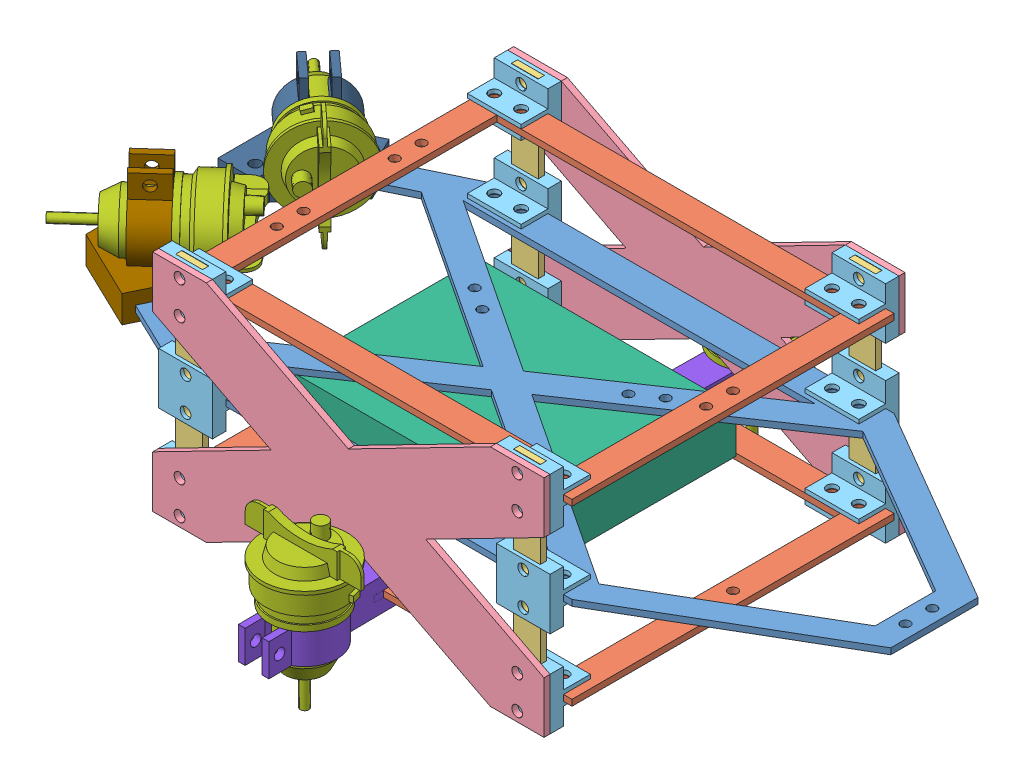
SolidWorks assembly Assem1, configuration Default. Lengths in mm.
Overall size (594.33 204.56 424.5).
30 component instances, 10 part files, 157 mates.
Components (placement in the parent):
- Middle Frame-1: Middle Frame [Default] at (261.8688 289.8887 390.3727) size (550 4.5 240)
- Top and Bottom Frames-1: Top and Bottom Frames [Default] at (113.8268 225.3887 390.3727) size (296 4.5 240)
- Top and Bottom Frames-2: Top and Bottom Frames [Default] at (113.8268 354.3887 390.3727) size (296 4.5 240)
- Rib-1: Rib [Default] at (261.8688 294.3887 512.9927) x (-1 0 0) z (0 0 1) size (20 167.5 4.5)
- Rib-3: Rib [Default] at (209.1848 289.8887 263.2527) size (20 167.5 4.5)
- Rib-4: Rib [Default] at (-42.4152 289.8887 262.9927) size (20 167.5 4.5)
- Rib-5: Rib [Default] at (-42.4152 291.8887 513.2527) size (20 167.5 4.5)
- Side Panels-3: Side Panels [Default] at (261.8688 354.3887 260.3727) x (-1 0 0) z (0 0 -1) size (291.6 167.5 4.5)
- Side Panels-4: Side Panels [Default] at (-42.4152 356.3887 520.3727) size (291.6 167.5 4.5)
- Joint-13: Joint [Default] at (10.2688 358.8887 390.3727) x (1 0 0) z (0 1 0) size (40 30 38.5)
- Joint-14: Joint [Default] at (10.2688 229.8887 390.3727) x (1 0 0) z (0 1 0) size (40 30 38.5)
- Joint-15: Joint [Default] at (10.2688 294.3887 390.3727) x (1 0 0) z (0 1 0) size (40 30 38.5)
- Joint-1: Joint [Default] at (261.8688 294.3887 390.3727) x (1 0 0) z (0 1 0) size (40 30 38.5)
- Joint-2: Joint [Default] at (261.8688 358.8887 390.3727) x (1 0 0) z (0 1 0) size (40 30 38.5)
- Joint-3: Joint [Default] at (261.8688 229.8887 390.3727) x (1 0 0) z (0 1 0) size (40 30 38.5)
- Joint-7: Joint [Default] at (209.2399 294.3887 390.3727) x (-1 0 0) z (0 1 0) size (40 30 38.5)
- Joint-8: Joint [Default] at (261.8688 354.3887 390.3727) x (1 0 0) z (0 -1 0) size (40 30 38.5)
- Joint-9: Joint [Default] at (261.8688 225.3887 390.3727) x (1 0 0) z (0 -1 0) size (40 30 38.5)
- Joint-10: Joint [Default] at (10.2688 354.3887 390.3727) x (1 0 0) z (0 -1 0) size (40 30 38.5)
- Joint-11: Joint [Default] at (10.2688 289.8887 390.3727) x (1 0 0) z (0 -1 0) size (40 30 38.5)
- Joint-12: Joint [Default] at (10.2688 225.3887 390.3727) x (1 0 0) z (0 -1 0) size (40 30 38.5)
- EBay-1: EBay [Default] at (261.8688 289.8887 390.3727) x (-1 0 0) z (0 -1 0) size (191.71 142.85 32)
- Thruster_CAD-2: Thruster_CAD [Default] at (-100.2352 324.4872 444.896) x (-0.743419 0 0.668826) z (0.668826 0 0.743419) size (115.62 62.99 86.36)
- Thruster_CAD-3: Thruster_CAD [Default] at (108.81 239.6387 223.1786) x (0 -1 0) z (-0.963048 0 -0.269329) size (115.62 62.99 86.36)
- Thruster_CAD-6: Thruster_CAD [Default] at (109.8463 239.6387 557.5668) x (0 -1 0) z (-1 0 0) size (115.62 62.99 86.36)
- Thruster_CAD-5: Thruster_CAD [Default] at (-100.2352 324.4872 335.8494) x (-0.743419 0 -0.668826) z (0 -1 0) size (115.62 62.99 86.36)
- Motor Mount A-2: Motor Mount A [Default] at (108.81 239.6387 223.1786) x (0.963048 0 0.269329) z (0 -1 0) size (55.77 118.28 24)
- Motor Mount A-3: Motor Mount A [Default] at (109.8463 215.6387 557.5668) x (0.963048 0 -0.269329) z (0 1 0) size (55.77 118.28 24)
- Motor Mount B1-2: Motor Mount B1 [Default] at (-100.2352 324.4872 444.896) x (-0.646037 -0.258819 -0.718087) z (-0.743419 0 0.668826) size (93.21 89.48 54.64)
- Motor Mount B2-1: Motor Mount B2 [Default] at (-100.2352 324.4872 335.8494) x (-0.646037 -0.258819 0.718087) z (0.743419 0 0.668826) size (93.21 89.48 54.64)
Mates (geometry in assembly coordinates):
- Concentric1: concentric aligned: circle of Middle Frame-1; circle of Top and Bottom Frames-2
- Parallel1: parallel aligned: line of Middle Frame-1 through (-34.1312 294.3887 510.3727) axis (1 0 0); line of Top and Bottom Frames-2 through (-34.1732 358.8887 510.3727) axis (1 0 0)
- Concentric2: concentric aligned: circle of Middle Frame-1; circle of Top and Bottom Frames-1
- Parallel2: parallel aligned: line of Middle Frame-1 through (-34.1312 294.3887 510.3727) axis (1 0 0); line of Top and Bottom Frames-1 through (-34.1732 229.8887 510.3727) axis (1 0 0)
- Distance1: distance = 60 mm: line of Top and Bottom Frames-2 through (-34.1732 354.3887 510.3727) axis (1 0 0); line of Middle Frame-1 through (-34.1312 294.3887 510.3727) axis (1 0 0)
- Distance2: distance = 60 mm: line of Top and Bottom Frames-1 through (-34.1732 229.8887 510.3727) axis (1 0 0); line of Middle Frame-1 through (-34.1312 289.8887 510.3727) axis (1 0 0)
- InPlace1: in place: plane of Middle Frame-1 through (261.8688 294.3887 390.3727) normal (0 1 0); plane of ? through (0 294.3887 0) normal (0 1 0); moOrthogonalPlaneRef_w of Middle Frame-1 through (261.8688 294.3887 390.3727) normal (0 1 0); plane of ? through (0 294.3887 0) normal (0 0 -1); plane of Middle Frame-1 through (261.8688 294.3887 390.3727) normal (0 1 0); plane of ? through (0 294.3887 0) normal (1 0 0); plane of Middle Frame-1 through (261.8688 294.3887 390.3727) normal (0 1 0); unknown of Joint-1
- Coincident5: coincident aligned: plane of ?; plane of ?
- Coincident6: coincident aligned: moOrthogonalPlaneRef_w of Middle Frame-1 through (261.8688 294.3887 390.3727) normal (0 0 -1); plane of Joint-1 through (261.8688 294.3887 390.3727) normal (0 0 -1)
- Coincident7: coincident anti-aligned: moOrthogonalPlaneRef_w of Middle Frame-1 through (261.8688 294.3887 390.3727) normal (-1 0 0); plane of Joint-1 through (261.8688 294.3887 390.3727) normal (1 0 0)
- Coincident19: coincident anti-aligned: plane of Top and Bottom Frames-2 through (-34.1732 358.8887 510.3727) normal (0 0 1); plane of Joint-2 through (261.8688 354.3887 510.3727) normal (0 0 -1)
- Concentric8: concentric aligned: circle of Top and Bottom Frames-2; circle of Part1-2
- Coincident21: coincident anti-aligned: plane of Top and Bottom Frames-2 through (113.8268 354.3887 390.3727) normal (0 -1 0); plane of Joint-2 through (261.8688 354.3887 390.3727) normal (0 1 0)
- Coincident22: coincident anti-aligned: plane of Top and Bottom Frames-1 through (-34.1732 229.8887 510.3727) normal (0 0 1); plane of Joint-3 through (261.8688 225.3887 510.3727) normal (0 0 -1)
- Concentric9: concentric aligned: circle of Top and Bottom Frames-1; circle of Part1-3
- Coincident24: coincident anti-aligned: plane of Top and Bottom Frames-1 through (113.8268 229.8887 390.3727) normal (0 1 0); plane of Joint-3 through (261.8688 229.8887 390.3727) normal (0 -1 0)
- InPlace2: in place: plane of Joint-1 through (261.8688 297.3887 512.9927) normal (0 0 1); plane of ? through (0 0 512.9927) normal (0 0 1); plane of Joint-1 through (261.8688 297.3887 512.9927) normal (0 0 1); plane of ? through (0 0 512.9927) normal (0 1 0); plane of Joint-1 through (261.8688 297.3887 512.9927) normal (0 0 1); plane of ? through (0 0 512.9927) normal (1 0 0); plane of Joint-1 through (261.8688 297.3887 512.9927) normal (0 0 1); unknown of Rib-1
- Coincident25: coincident aligned: plane of ?; plane of ?
- Coincident26: coincident aligned: moOrthogonalPlaneRef_w of Joint-1 through (261.8688 294.3887 512.9927) normal (0 -1 0); plane of Rib-1 through (261.8688 294.3887 512.9927) normal (0 -1 0)
- Coincident27: coincident anti-aligned: moOrthogonalPlaneRef_w of Joint-1 through (261.8688 294.3887 512.9927) normal (1 0 0); plane of Rib-1 through (261.8688 294.3887 512.9927) normal (-1 0 0)
- InPlace3: in place: plane of Middle Frame-1 through (261.8688 294.3887 390.3727) normal (0 1 0); plane of ? through (0 294.3887 0) normal (0 1 0); plane of Middle Frame-1 through (261.8688 294.3887 390.3727) normal (0 1 0); plane of ? through (0 294.3887 0) normal (0 0 -1); plane of Middle Frame-1 through (261.8688 294.3887 390.3727) normal (0 1 0); plane of ? through (0 294.3887 0) normal (1 0 0); plane of Middle Frame-1 through (261.8688 294.3887 390.3727) normal (0 1 0); unknown of Joint-1
- Coincident25: coincident aligned: plane of ?; plane of ?
- Coincident26: coincident aligned: moOrthogonalPlaneRef_w of Middle Frame-1 through (261.8688 294.3887 390.3727) normal (0 0 -1); plane of Part3-1 through (261.8688 294.3887 390.3727) normal (0 0 -1)
- Coincident27: coincident anti-aligned: moOrthogonalPlaneRef_w of Middle Frame-1 through (261.8688 294.3887 390.3727) normal (-1 0 0); plane of Part3-1 through (261.8688 294.3887 390.3727) normal (1 0 0)
- Coincident31: coincident anti-aligned: plane of Top and Bottom Frames-2 through (261.8268 358.8887 510.3727) normal (1 0 0); plane of Part4-1 through (261.8268 354.3887 391.9497) normal (-1 0 0)
- Coincident32: coincident anti-aligned: plane of Top and Bottom Frames-2 through (113.8268 354.3887 390.3727) normal (0 -1 0); plane of Part4-1 through (391.8268 354.3887 391.9497) normal (0 1 0)
- Concentric11: concentric aligned: circle of Top and Bottom Frames-2; circle of Part3-2
- InPlace4: in place: plane of Top and Bottom Frames-2 through (113.8268 358.8887 390.3727) normal (0 1 0); plane of ? through (0 358.8887 0) normal (0 1 0); plane of Top and Bottom Frames-2 through (113.8268 358.8887 390.3727) normal (0 1 0); plane of ? through (0 358.8887 0) normal (0 0 -1); plane of Top and Bottom Frames-2 through (113.8268 358.8887 390.3727) normal (0 1 0); plane of ? through (0 358.8887 0) normal (1 0 0); plane of Top and Bottom Frames-2 through (113.8268 358.8887 390.3727) normal (0 1 0); unknown of ?
- Coincident35: coincident aligned: plane of ?; plane of ?
- Coincident36: coincident aligned: moOrthogonalPlaneRef_w of Top and Bottom Frames-2 through (113.8268 358.8887 390.3727) normal (0 0 -1); plane of Front Rib-2 through (113.8268 358.8887 390.3727) normal (0 0 -1)
- Coincident37: coincident anti-aligned: moOrthogonalPlaneRef_w of Top and Bottom Frames-2 through (113.8268 358.8887 390.3727) normal (-1 0 0); plane of Front Rib-2 through (113.8268 358.8887 390.3727) normal (1 0 0)
- Coincident38: coincident anti-aligned: plane of Top and Bottom Frames-1 through (261.8268 229.8887 510.3727) normal (1 0 0); plane of Part4-2 through (261.8268 229.8887 388.7957) normal (-1 0 0)
- Coincident39: coincident anti-aligned: plane of Top and Bottom Frames-1 through (113.8268 225.3887 390.3727) normal (0 -1 0); plane of Part4-2 through (391.8268 225.3887 388.7957) normal (0 1 0)
- Concentric12: concentric anti-aligned: circle of Top and Bottom Frames-1; circle of Part4-2
- Coincident41: coincident anti-aligned: plane of Part4-2 through (266.8688 225.3887 386.5457) normal (0 1 0); plane of Front Rib-3 through (539.9108 225.3887 390.3727) normal (0 -1 0)
- Coincident42: coincident anti-aligned: plane of Part4-2 through (391.8268 225.3887 386.5457) normal (0 0 1); plane of Front Rib-3 through (386.8688 225.3887 386.5457) normal (0 0 -1)
- Coincident43: coincident anti-aligned: plane of Part4-2 through (276.8268 231.2277 386.5457) normal (0.50582 -0.862639 0); plane of Front Rib-3 through (498.1959 361.0305 386.5457) normal (-0.50582 0.862639 0)
- InPlace5: in place: plane of Middle Frame-1 through (261.8688 289.8887 390.3727) normal (0 -1 0); plane of ? through (0 289.8887 0) normal (0 -1 0); plane of Middle Frame-1 through (261.8688 289.8887 390.3727) normal (0 -1 0); plane of ? through (0 289.8887 0) normal (0 0 -1); plane of Middle Frame-1 through (261.8688 289.8887 390.3727) normal (0 -1 0); plane of ? through (0 289.8887 0) normal (-1 0 0); plane of Middle Frame-1 through (261.8688 289.8887 390.3727) normal (0 -1 0); unknown of EBay-1
- Coincident44: coincident aligned: plane of ?; plane of ?
- Coincident45: coincident aligned: moOrthogonalPlaneRef_w of Middle Frame-1 through (261.8688 289.8887 390.3727) normal (0 0 -1); plane of Part4^Assem1-1 through (261.8688 289.8887 390.3727) normal (0 0 -1)
- Coincident46: coincident anti-aligned: moOrthogonalPlaneRef_w of Middle Frame-1 through (261.8688 289.8887 390.3727) normal (1 0 0); plane of Part4^Assem1-1 through (261.8688 289.8887 390.3727) normal (-1 0 0)
- InPlace6: in place: plane of ? through (200.9485 144.8042 552.0146) normal (1 0 0); plane of ? through (200.9485 0 0) normal (1 0 0); plane of ? through (200.9485 144.8042 552.0146) normal (1 0 0); plane of ? through (200.9485 0 0) normal (0 1 0); plane of ? through (200.9485 144.8042 552.0146) normal (1 0 0); plane of ? through (200.9485 0 0) normal (0 0 -1); plane of ? through (264.6716 329.6787 371.9722) normal (-1 0 0); unknown of ?
- Coincident47: coincident aligned: plane of ?; plane of ?
- Coincident48: coincident aligned: moOrthogonalPlaneRef_w of Thruster_CAD-1 through (264.6716 329.6787 371.9722) normal (0 1 0); plane of Part5^Assem1-1 through (264.6716 329.6787 371.9722) normal (0 1 0)
- Coincident49: coincident anti-aligned: moOrthogonalPlaneRef_w of Thruster_CAD-1 through (264.6716 329.6787 371.9722) axis (0 0 -1); plane of Part5^Assem1-1 through (264.6716 329.6787 371.9722) normal (0 0 1)
- Tangent1: tangent aligned: plane of Top and Bottom Frames-2 through (113.8268 358.8887 390.3727) normal (0 1 0); cylinder of Thruster_CAD-1 through (413.065 329.6787 580.763) axis (-1 0 0) radius 29.21
- Parallel3: parallel aligned: plane of Top and Bottom Frames-2 through (113.8268 358.8887 390.3727) normal (0 1 0); plane of Thruster_CAD-1 through (415.605 332.8537 537.583) normal (0 1 0)
- Parallel4: parallel aligned: plane of Top and Bottom Frames-2 through (261.8268 358.8887 510.3727) normal (1 0 0); plane of Thruster_CAD-1 through (423.225 329.6787 580.763) normal (1 0 0)
- InPlace7: in place: plane of ? through (-212.6065 302.1229 334.1009) normal (0.225062 0.973817 -0.032065); plane of ? through (53.0358 229.4795 -7.5562) normal (0.225062 0.973817 -0.032065); plane of ? through (-212.6065 302.1229 334.1009) normal (0.225062 0.973817 -0.032065); plane of ? through (53.0358 229.4795 -7.5562) normal (0 -0.03291 -0.999458); plane of ? through (-212.6065 302.1229 334.1009) normal (0.225062 0.973817 -0.032065); plane of ? through (53.0358 229.4795 -7.5562) normal (0.974344 -0.22494 0.007407); plane of Thruster_CAD-2 through (-81.8879 325.6302 465.2895) normal (0 1 0); unknown of ?
- Coincident51: coincident aligned: plane of ?; plane of ?
- Coincident52: coincident aligned: moOrthogonalPlaneRef_w of Thruster_CAD-2; plane of Part6-1 through (-175.4369 294.3887 312.5064) normal (0.564879 0 -0.825174)
- Coincident53: coincident anti-aligned: moOrthogonalPlaneRef_w of Thruster_CAD-2; plane of Part6-1 through (-175.4369 294.3887 312.5064) normal (0.825174 0 0.564879)
- Coincident84: coincident: line of Middle Frame-1 through (-118.1312 294.3887 332.9487) axis (0.901252 0 -0.433294); point of Part6-1
- Coincident88: coincident: line of Middle Frame-1 through (-50.4474 294.3887 480.337) axis (-0.901252 0 -0.433294); point of Part6-2
- Coincident91: coincident anti-aligned: plane of Middle Frame-1 through (261.8688 294.3887 390.3727) normal (0 1 0); plane of Part6-1 through (-175.4369 294.3887 312.5064) normal (0 -1 0)
- Coincident92: coincident anti-aligned: plane of Middle Frame-1 through (261.8688 294.3887 390.3727) normal (0 1 0); plane of Part6-2 through (-175.4369 294.3887 468.239) normal (0 -1 0)
- InPlace8: in place: plane of ? through (220.4652 380.7728 388.8084) normal (0.784946 -0.070788 -0.615507); plane of ? through (-73.1687 6.5985 57.3744) normal (0.784946 -0.070788 -0.615507); plane of ? through (220.4652 380.7728 388.8084) normal (0.784946 -0.070788 -0.615507); plane of ? through (-73.1687 6.5985 57.3744) normal (0.089817 0.995958 0); plane of ? through (220.4652 380.7728 388.8084) normal (0.784946 -0.070788 -0.615507); plane of ? through (-73.1687 6.5985 57.3744) normal (-0.613019 0.055283 -0.788132); plane of Thruster_CAD-3 through (134.9205 239.6387 231.6677) normal (-0.269329 0 0.963048); unknown of ?
- Coincident93: coincident aligned: plane of ?; plane of ?
- Coincident94: coincident aligned: moOrthogonalPlaneRef_w of Thruster_CAD-3; plane of Part7-1 through (237.3268 414.4075 390.3727) normal (0 0 1)
- Coincident95: coincident anti-aligned: moOrthogonalPlaneRef_w of Thruster_CAD-3; plane of Part7-1 through (237.3268 414.4075 390.3727) normal (0 1 0)
- Coincident100: coincident anti-aligned: plane of Top and Bottom Frames-2 through (241.8268 358.8887 290.3727) normal (-1 0 0); plane of Part7-1 through (241.8268 414.4075 390.3727) normal (1 0 0)
- Coincident101: coincident anti-aligned: plane of Top and Bottom Frames-2 through (113.8268 358.8887 390.3727) normal (0 1 0); plane of Part7-1 through (261.8268 358.8887 390.3727) normal (0 -1 0)
- Coincident102: coincident: moEndPointRef_w of Top and Bottom Frames-2; unknown of Part7-1
- Coincident125: coincident anti-aligned: plane of Middle Frame-1 through (261.8688 294.3887 390.3727) normal (0 1 0); plane of Part6-1 through (-175.4369 294.3887 312.5064) normal (0 -1 0)
- Concentric19: concentric aligned: circle of Middle Frame-1; circle of Part6-1
- InPlace9: in place: plane of Top and Bottom Frames-1 through (113.8268 225.3887 390.3727) normal (0 -1 0); plane of ? through (0 225.3887 0) normal (0 -1 0); plane of Top and Bottom Frames-1 through (113.8268 225.3887 390.3727) normal (0 -1 0); plane of ? through (0 225.3887 0) normal (0 0 -1); plane of Top and Bottom Frames-1 through (113.8268 225.3887 390.3727) normal (0 -1 0); plane of ? through (0 225.3887 0) normal (-1 0 0); plane of Top and Bottom Frames-1 through (113.8268 225.3887 390.3727) normal (0 -1 0); unknown of ?
- Coincident127: coincident aligned: plane of ?; plane of ?
- Coincident128: coincident aligned: moOrthogonalPlaneRef_w of Top and Bottom Frames-1 through (113.8268 225.3887 390.3727) normal (0 0 -1); plane of Part8^Assem1-1 through (113.8268 225.3887 390.3727) normal (0 0 -1)
- Coincident129: coincident anti-aligned: moOrthogonalPlaneRef_w of Top and Bottom Frames-1 through (113.8268 225.3887 390.3727) normal (1 0 0); plane of Part8^Assem1-1 through (113.8268 225.3887 390.3727) normal (-1 0 0)
- InPlace10: in place: plane of ? through (25.378 345.2649 355.2944) normal (0 1 0); plane of ? through (0 345.2649 0) normal (0 1 0); plane of ? through (25.378 345.2649 355.2944) normal (0 1 0); plane of ? through (0 345.2649 0) normal (0 0 -1); plane of ? through (25.378 345.2649 355.2944) normal (0 1 0); plane of ? through (0 345.2649 0) normal (1 0 0); plane of ? through (34.5956 220.8887 362.9407) normal (0 1 0); unknown of ?
- Coincident130: coincident aligned: plane of ?; plane of ?
- Coincident131: coincident aligned: moOrthogonalPlaneRef_w of Thruster_CAD-4 through (34.5956 220.8887 390.3727) normal (0 0 -1); plane of Part9^Assem1-1 through (34.5956 220.8887 390.3727) normal (0 0 -1)
- Coincident132: coincident anti-aligned: moOrthogonalPlaneRef_w of Thruster_CAD-4 through (34.5956 220.8887 390.3727) normal (-1 0 0); plane of Part9^Assem1-1 through (34.5956 220.8887 390.3727) normal (1 0 0)
- Coincident133: coincident anti-aligned: plane of Top and Bottom Frames-1 through (113.8268 225.3887 390.3727) normal (0 -1 0); plane of Part9^Assem1-1 through (34.5956 225.3887 390.3727) normal (0 1 0)
- Coincident134: coincident: unknown of Part9^Assem1-1; unknown of Top and Bottom Frames-1
- Parallel12: parallel anti-aligned: line of Top and Bottom Frames-1 through (-34.1732 225.3887 270.3727) axis (0 0 1); line of Part9^Assem1-1 through (-34.1732 225.3887 453.5527) axis (0 0 -1)
- Coincident137: coincident anti-aligned: plane of Middle Frame-1 through (261.8688 294.3887 270.3727) normal (0 0 -1); plane of Joint-7 through (209.2399 289.8887 270.3727) normal (0 0 1)
- Coincident138: coincident anti-aligned: plane of Middle Frame-1 through (261.8688 289.8887 390.3727) normal (0 -1 0); plane of Joint-7 through (209.2399 289.8887 390.3727) normal (0 1 0)
- Concentric20: concentric anti-aligned: circle of Middle Frame-1; circle of Part1-7
- Coincident140: coincident anti-aligned: plane of Top and Bottom Frames-2 through (-34.1732 358.8887 270.3727) normal (0 0 -1); plane of Joint-8 through (261.8688 358.8887 270.3727) normal (0 0 1)
- Coincident141: coincident anti-aligned: plane of Top and Bottom Frames-2 through (113.8268 354.3887 390.3727) normal (0 -1 0); plane of Joint-8 through (261.8688 354.3887 390.3727) normal (0 1 0)
- Concentric21: concentric aligned: circle of Top and Bottom Frames-2; circle of Part1-8
- Coincident143: coincident anti-aligned: plane of Top and Bottom Frames-1 through (-34.1732 229.8887 270.3727) normal (0 0 -1); plane of Joint-9 through (261.8688 229.8887 270.3727) normal (0 0 1)
- Coincident144: coincident anti-aligned: plane of Top and Bottom Frames-1 through (113.8268 225.3887 390.3727) normal (0 -1 0); plane of Joint-9 through (261.8688 225.3887 390.3727) normal (0 1 0)
- Concentric22: concentric aligned: circle of Top and Bottom Frames-1; circle of Part1-9
- Coincident148: coincident aligned: circle of Part1-8; circle of Part2-3
- Coincident149: coincident anti-aligned: plane of Joint-8 through (245.5268 351.3887 390.3727) normal (-1 0 0); plane of Rib-3 through (245.5268 207.3887 267.7527) normal (1 0 0)
- Coincident150: coincident anti-aligned: plane of Top and Bottom Frames-2 through (113.8268 358.8887 390.3727) normal (0 1 0); plane of Joint-10 through (10.2688 358.8887 390.3727) normal (0 -1 0)
- Coincident151: coincident anti-aligned: plane of Top and Bottom Frames-2 through (-34.1732 358.8887 270.3727) normal (0 0 -1); plane of Joint-10 through (10.2688 358.8887 270.3727) normal (0 0 1)
- Concentric25: concentric aligned: circle of Top and Bottom Frames-2; circle of Part1-10
- Coincident153: coincident anti-aligned: plane of Middle Frame-1 through (261.8688 294.3887 270.3727) normal (0 0 -1); plane of Joint-11 through (10.2688 294.3887 270.3727) normal (0 0 1)
- Coincident154: coincident anti-aligned: plane of Middle Frame-1 through (261.8688 289.8887 390.3727) normal (0 -1 0); plane of Joint-11 through (10.2688 289.8887 390.3727) normal (0 1 0)
- Concentric26: concentric aligned: circle of Middle Frame-1; circle of Part1-11
- Coincident156: coincident anti-aligned: plane of Top and Bottom Frames-1 through (-34.1732 229.8887 270.3727) normal (0 0 -1); plane of Joint-12 through (10.2688 229.8887 270.3727) normal (0 0 1)
- Coincident157: coincident anti-aligned: plane of Top and Bottom Frames-1 through (113.8268 225.3887 390.3727) normal (0 -1 0); plane of Joint-12 through (10.2688 225.3887 390.3727) normal (0 1 0)
- Concentric27: concentric aligned: circle of Top and Bottom Frames-1; circle of Part1-12
- Coincident159: coincident aligned: circle of Part1-10; circle of Part2-4
- Coincident161: coincident anti-aligned: plane of Joint-10 through (10.2688 351.3887 262.9927) normal (0 0 1); plane of Rib-4 through (-42.4152 289.8887 262.9927) normal (0 0 -1)
- Coincident162: coincident anti-aligned: plane of Joint-10 through (-6.0732 351.3887 390.3727) normal (-1 0 0); plane of Rib-4 through (-6.0732 207.3887 267.4927) normal (1 0 0)
- Coincident163: coincident anti-aligned: plane of Top and Bottom Frames-2 through (-34.1732 358.8887 510.3727) normal (0 0 1); plane of Joint-13 through (10.2688 354.3887 510.3727) normal (0 0 -1)
- Coincident164: coincident anti-aligned: plane of Top and Bottom Frames-2 through (113.8268 354.3887 390.3727) normal (0 -1 0); plane of Joint-13 through (10.2688 354.3887 390.3727) normal (0 1 0)
- Concentric28: concentric aligned: circle of Top and Bottom Frames-2; circle of Part1-13
- Coincident166: coincident anti-aligned: plane of Middle Frame-1 through (261.8688 294.3887 510.3727) normal (0 0 1); plane of Joint-15 through (10.2688 289.8887 510.3727) normal (0 0 -1)
- Coincident167: coincident anti-aligned: plane of Middle Frame-1 through (261.8688 289.8887 390.3727) normal (0 -1 0); plane of Joint-15 through (10.2688 289.8887 390.3727) normal (0 1 0)
- Concentric29: concentric aligned: circle of Middle Frame-1; circle of Part1-15
- Coincident169: coincident anti-aligned: plane of Top and Bottom Frames-1 through (-34.1732 229.8887 510.3727) normal (0 0 1); plane of Joint-14 through (10.2688 225.3887 510.3727) normal (0 0 -1)
- Coincident170: coincident anti-aligned: plane of Top and Bottom Frames-1 through (113.8268 229.8887 390.3727) normal (0 1 0); plane of Joint-14 through (10.2688 229.8887 390.3727) normal (0 -1 0)
- Concentric30: concentric aligned: circle of Top and Bottom Frames-1; circle of Part1-14
- Coincident172: coincident anti-aligned: circle of Part1-13; circle of Part2-5
- Coincident173: coincident anti-aligned: plane of Joint-13 through (-26.0732 361.8887 390.3727) normal (1 0 0); plane of Rib-5 through (-26.0732 209.3887 517.7527) normal (-1 0 0)
- Coincident174: coincident anti-aligned: plane of Top and Bottom Frames-1 through (241.8268 229.8887 290.3727) normal (-1 0 0); plane of Part7-3 through (241.8268 169.8699 390.3727) normal (1 0 0)
- Coincident175: coincident anti-aligned: plane of Top and Bottom Frames-1 through (113.8268 225.3887 390.3727) normal (0 -1 0); plane of Part7-3 through (261.8268 225.3887 390.3727) normal (0 1 0)
- Concentric31: concentric anti-aligned: circle of Top and Bottom Frames-1; circle of Part7-3
- Coincident178: coincident aligned: line of Part6-1 through (-138.1312 294.3887 390.3727) axis (-0.825174 0 0.564879); line of Thruster_CAD-5 through (-72.6376 367.6672 362.2154) axis (-0.743419 0 -0.668826)
- Coincident179: coincident anti-aligned: line of Part6-1 through (-126.481 294.3887 487.0543) axis (0.825174 0 -0.564879); line of Thruster_CAD-5 through (-72.6376 281.3072 362.2154) axis (-0.743419 0 -0.668826)
- Coincident180: coincident aligned: line of Part6-1 through (-134.3893 294.3887 475.5018) axis (0.564879 0 0.825174); line of Thruster_CAD-5 through (-78.869 293.0119 356.6093) axis (0 -1 0)
- Coincident181: coincident anti-aligned: line of Part7-3 through (237.3268 199.6387 347.1927) axis (0 0 1); line of Thruster_CAD-6 through (141.3215 269.4075 558.7098) axis (1 0 0)
- Coincident182: coincident anti-aligned: plane of Part7-3 through (237.3268 169.8699 390.3727) normal (-1 0 0); plane of Thruster_CAD-6 through (82.4143 239.6387 558.7098) normal (0 0 1)
- Coincident183: coincident anti-aligned: line of Part7-3 through (237.3268 199.6387 433.5527) axis (0 0 -1); line of Thruster_CAD-6 through (78.371 269.4075 558.7098) axis (-1 0 0)
- Coincident184: coincident anti-aligned: line of Part7-3 through (237.3268 199.6387 347.1927) axis (0 1 0); line of Thruster_CAD-6 through (153.0263 277.7895 558.7098) axis (0 -1 0)
- InPlace11: in place: plane of ? through (84.5471 182.5692 222.8071) normal (0.202423 0.975332 -0.088042); plane of ? through (35.5381 171.2328 -15.457) normal (0.202423 0.975332 -0.088042); plane of ? through (84.5471 182.5692 222.8071) normal (0.202423 0.975332 -0.088042); plane of ? through (35.5381 171.2328 -15.457) normal (0 -0.089904 -0.99595); plane of ? through (84.5471 182.5692 222.8071) normal (0.202423 0.975332 -0.088042); plane of ? through (35.5381 171.2328 -15.457) normal (0.979298 -0.201603 0.018199); plane of Thruster_CAD-3 through (108.81 239.6387 223.1786) normal (0 -1 0); unknown of Motor Mount A-2
- Coincident185: coincident aligned: plane of ?; plane of ?
- Coincident186: coincident aligned: moOrthogonalPlaneRef_w of Thruster_CAD-3; plane of Motor Mount A-2 through (108.81 239.6387 223.1786) normal (-0.269329 0 0.963048)
- Coincident187: coincident anti-aligned: moOrthogonalPlaneRef_w of Thruster_CAD-3; plane of Motor Mount A-2 through (108.81 239.6387 223.1786) normal (0.963048 0 0.269329)
- InPlace12: in place: plane of Joint-8 through (261.8688 351.3887 260.3727) normal (0 0 -1); plane of ? through (0 0 260.3727) normal (0 0 -1); plane of Joint-8 through (261.8688 351.3887 260.3727) normal (0 0 -1); plane of ? through (0 0 260.3727) normal (0 1 0); plane of Joint-8 through (261.8688 351.3887 260.3727) normal (0 0 -1); plane of ? through (0 0 260.3727) normal (-1 0 0); plane of Joint-8 through (261.8688 351.3887 260.3727) normal (0 0 -1); unknown of Side Panels-3
- Coincident188: coincident aligned: plane of ?; plane of ?
- Coincident189: coincident aligned: moOrthogonalPlaneRef_w of Joint-8 through (261.8688 354.3887 260.3727) normal (0 1 0); plane of Side Panels-3 through (261.8688 354.3887 260.3727) normal (0 1 0)
- Coincident190: coincident anti-aligned: moOrthogonalPlaneRef_w of Joint-8 through (261.8688 354.3887 260.3727) normal (1 0 0); plane of Side Panels-3 through (261.8688 354.3887 260.3727) normal (-1 0 0)
- Concentric32: concentric aligned: circle of Part1-13; circle of side panels-4
- Coincident193: coincident anti-aligned: plane of Joint-13 through (10.2688 361.8887 520.3727) normal (0 0 1); plane of Side Panels-4 through (-42.4152 356.3887 520.3727) normal (0 0 -1)
- Parallel13: parallel anti-aligned: line of Joint-13 through (3.9268 376.8887 520.3727) axis (-1 0 0); line of Side Panels-4 through (-36.0732 376.8887 524.8727) axis (1 0 0)
- Concentric35: concentric aligned: cylinder of Thruster_CAD-2 through (-121.1951 324.4872 463.7529) axis (0.743419 0 -0.668826) radius 20.193; cylinder of Motor Mount B1-1 through (-118.0772 324.4872 460.9478) axis (0.743419 0 -0.668826) radius 20.193
- Coincident194: coincident anti-aligned: plane of Thruster_CAD-2 through (-100.2352 324.4872 444.896) normal (-0.743419 0 0.668826); plane of Motor Mount B1-1 through (-100.2352 324.4872 444.896) normal (0.743419 0 -0.668826)
- Parallel14: parallel aligned: plane of Thruster_CAD-2 through (-49.2246 321.3122 457.0867) normal (-0.743419 0 0.668826); plane of Motor Mount B1-1 through (-118.0772 324.4872 460.9478) normal (-0.743419 0 0.668826)
- Parallel15: parallel anti-aligned: plane of Top and Bottom Frames-1 through (113.8268 229.8887 390.3727) normal (0 1 0); plane of Motor Mount A-2 through (108.81 215.6387 223.1786) normal (0 -1 0)
- Coincident199: coincident anti-aligned: plane of Top and Bottom Frames-1 through (113.8268 229.8887 390.3727) normal (0 1 0); plane of Motor Mount A-2 through (108.81 229.8887 263.8727) normal (0 -1 0)
- Coincident200: coincident anti-aligned: plane of Top and Bottom Frames-1 through (-34.1732 229.8887 270.3727) normal (0 0 -1); plane of Motor Mount A-2 through (108.81 239.6387 270.3727) normal (0 0 1)
- Concentric36: concentric anti-aligned: cylinder of Thruster_CAD-6 through (109.8463 211.4447 557.5668) axis (0 1 0) radius 20.193; cylinder of Motor Mount A-3 through (109.8463 239.6387 557.5668) axis (0 -1 0) radius 20.193
- Coincident201: coincident anti-aligned: plane of Thruster_CAD-6 through (109.8463 239.6387 557.5668) normal (0 -1 0); plane of Motor Mount A-3 through (109.8463 239.6387 557.5668) normal (0 1 0)
- Parallel16: parallel anti-aligned: plane of Thruster_CAD-6 through (137.2783 239.6387 558.7098) normal (0 0 1); plane of Motor Mount A-3 through (109.8463 215.6387 479.8727) normal (0 0 -1)
- Coincident203: coincident anti-aligned: plane of Top and Bottom Frames-1 through (113.8268 225.3887 390.3727) normal (0 -1 0); plane of Motor Mount A-3 through (109.8463 225.3887 516.8727) normal (0 1 0)
- Coincident204: coincident anti-aligned: plane of Top and Bottom Frames-1 through (-34.1732 229.8887 510.3727) normal (0 0 1); plane of Motor Mount A-3 through (109.8463 215.6387 510.3727) normal (0 0 -1)
- Parallel17: parallel anti-aligned: plane of Motor Mount A-2 through (108.81 239.6387 300.8727) normal (0 0 1); plane of Motor Mount A-3 through (109.8463 215.6387 479.8727) normal (0 0 -1)
- Parallel22: parallel aligned: plane of Thruster_CAD-2 through (-81.8879 325.6302 465.2895) normal (0 1 0); plane of Motor Mount B1-1 through (-100.2352 362.8993 444.896) normal (0 1 0)
- Parallel24: parallel anti-aligned: plane of Top and Bottom Frames-2 through (113.8268 358.8887 390.3727) normal (0 1 0); plane of Thruster_CAD-2 through (-81.8879 323.3442 465.2895) normal (0 -1 0)
- Concentric37: concentric aligned: cylinder of Thruster_CAD-2 through (-121.1951 324.4872 463.7529) axis (0.743419 0 -0.668826) radius 20.193; cylinder of Motor Mount B1-2 through (-118.0772 324.4872 460.9478) axis (0.743419 0 -0.668826) radius 20.193
- Coincident206: coincident anti-aligned: circle of Thruster_CAD-2; plane of Motor Mount B1-2 through (-100.2352 324.4872 444.896) normal (0.743419 0 -0.668826)
- Parallel25: parallel aligned: plane of Thruster_CAD-2 through (-118.5824 325.6302 424.5026) normal (0 1 0); plane of Motor Mount B1-2 through (-100.2352 362.8993 444.896) normal (0 1 0)
- Coincident208: coincident anti-aligned: plane of Middle Frame-1 through (261.8688 289.8887 390.3727) normal (0 -1 0); plane of Motor Mount B1-2 through (-100.2352 289.8887 444.896) normal (0 1 0)
- Coincident209: coincident anti-aligned: line of Middle Frame-1 through (-138.1312 294.3887 460.3727) axis (0 -1 0); line of Motor Mount B1-2 through (-138.1312 289.8887 460.3727) axis (0 1 0)
- Coincident210: coincident anti-aligned: plane of Middle Frame-1 through (-138.1312 294.3887 390.3727) normal (-1 0 0); plane of Motor Mount B1-2 through (-138.1312 289.8887 444.896) normal (1 0 0)
- Concentric38: concentric aligned: cylinder of Thruster_CAD-5 through (-121.1951 324.4872 316.9925) axis (0.743419 0 0.668826) radius 20.193; cylinder of MirrorMotor Mount B1-5 through (-118.0772 324.4872 319.7976) axis (0.743419 0 0.668826) radius 20.193
- Coincident211: coincident anti-aligned: circle of Thruster_CAD-5; plane of MirrorMotor Mount B1-5 through (-100.2352 324.4872 335.8494) normal (0.743419 0 0.668826)
- Parallel26: parallel aligned: plane of Thruster_CAD-5 through (-99.4707 297.0552 334.9997) normal (0.668826 0 -0.743419); plane of MirrorMotor Mount B1-5 through (-92.7031 324.4872 327.4773) normal (0.668826 0 -0.743419)
- Coincident213: coincident anti-aligned: plane of Middle Frame-1 through (261.8688 289.8887 390.3727) normal (0 -1 0); plane of MirrorMotor Mount B1-5 through (-100.2352 289.8887 335.8494) normal (0 1 0)
- Coincident214: coincident anti-aligned: line of Middle Frame-1 through (-138.1312 294.3887 320.3727) axis (0 -1 0); line of MirrorMotor Mount B1-5 through (-138.1312 289.8887 320.3727) axis (0 1 0)
- Coincident215: coincident anti-aligned: plane of Middle Frame-1 through (-138.1312 294.3887 390.3727) normal (-1 0 0); plane of MirrorMotor Mount B1-5 through (-138.1312 289.8887 335.8494) normal (1 0 0)
